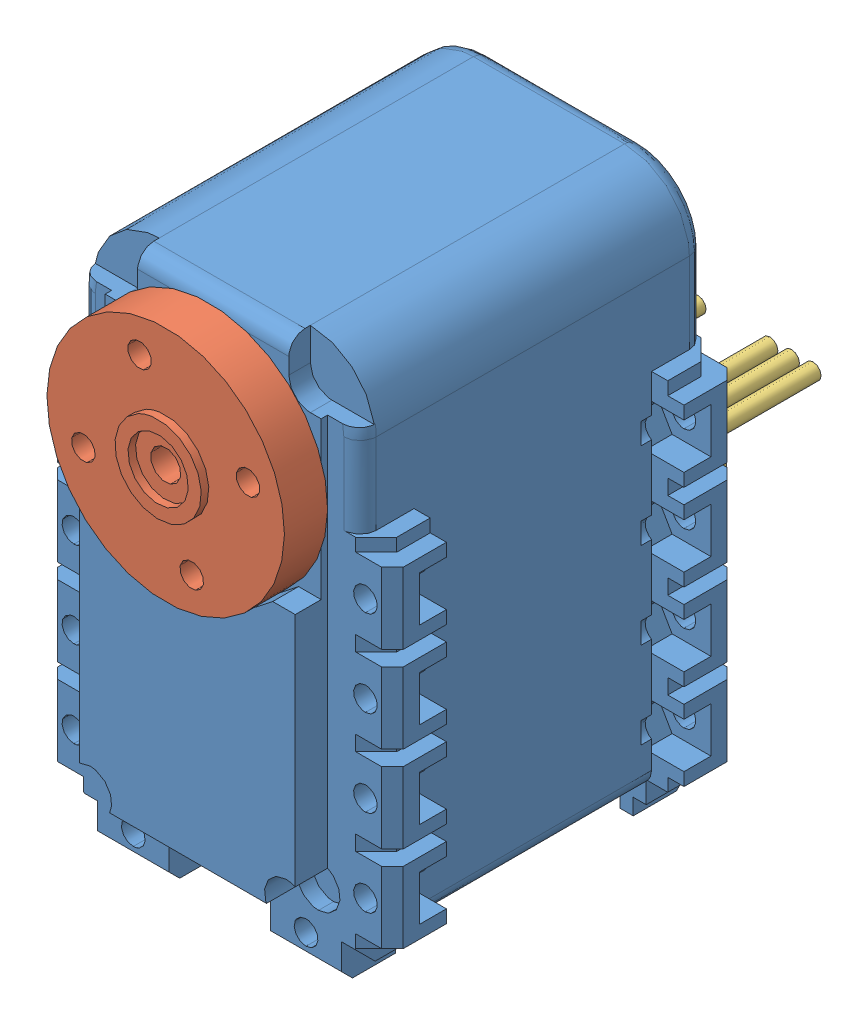
SolidWorks assembly servomoteur_ax-12, configuration Default. Lengths in mm.
Overall size (32 52.31 53.4).
4 component instances, 3 part files, 8 mates.
Components (placement in the parent):
- AX-12_modif-1: AX-12_modif [Défaut] at (-2.6768 21.8769 -4.3025) size (32 50.06 38.01)
- attache_ax-12-1: attache_ax-12 [Default] at (-2.6768 21.8769 12.6975) x (-0.301968 0.953318 0) z (0 0 1) size (22 22 4.7)
- connecteur_AX-12-1: connecteur_AX-12 [Default] at (6.5732 8.6769 -17.5025) x (-1 0 0) z (0 -1 0) size (8 18.5 4)
- connecteur_AX-12-2: connecteur_AX-12 [Default] at (-4.0768 8.6769 -17.5025) x (-1 0 0) z (0 -1 0) size (8 18.5 4)
Mates (geometry in assembly coordinates):
- Coïncidente1: coincident: plane of AX-12_modif-1 through (8.7632 10.4369 12.6975) normal (0 0 1); plane of attache_ax-12-1 through (-2.6768 21.8769 12.6975) normal (0 0 -1)
- Tangent6: tangent: face of AX-12_modif-1; cylinder of attache_ax-12-1 through (-2.6768 21.8769 12.6965) axis (0 0 1) radius 1.4
- Coïncidente7: coincident: plane of AX-12_modif-1 through (7.7232 8.7632 -17.5025) normal (0 0 -1); plane of connecteur_AX-12-1 through (6.5732 8.6769 -17.5025) normal (0 0 1)
- Coïncidente8: coincident: plane of AX-12_modif-1 through (7.7232 8.7632 -17.5025) normal (0 0 -1); plane of connecteur_AX-12-2 through (-27.3854 8.6769 -17.5025) normal (0 0 1)
- Distance2: distance = 0.75 mm: plane of connecteur_AX-12-1 through (6.5732 5.6769 -21.5025) normal (1 0 0); plane of AX-12_modif-1 through (7.3232 11.0509 -17.4162) normal (-1 0 0)
- Coïncidente11: coincident: line of AX-12_modif-1 through (7.3232 8.6769 -17.5025) axis (-1 0 0); line of connecteur_AX-12-1 through (-1.4268 7.9938 -17.5025) axis (1 0 0)
- Coïncidente12: coincident: line of AX-12_modif-1 through (-12.6768 8.6769 -17.5025) axis (1 0 0); line of connecteur_AX-12-2 through (-35.3854 8.6769 -17.5025) axis (1 0 0)
- Distance3: distance = 0.75 mm anti-aligned: plane of connecteur_AX-12-2 through (-4.0768 5.6769 -21.5025) normal (1 0 0); plane of AX-12_modif-1 through (-3.3268 11.0509 -20.3889) normal (-1 0 0)
